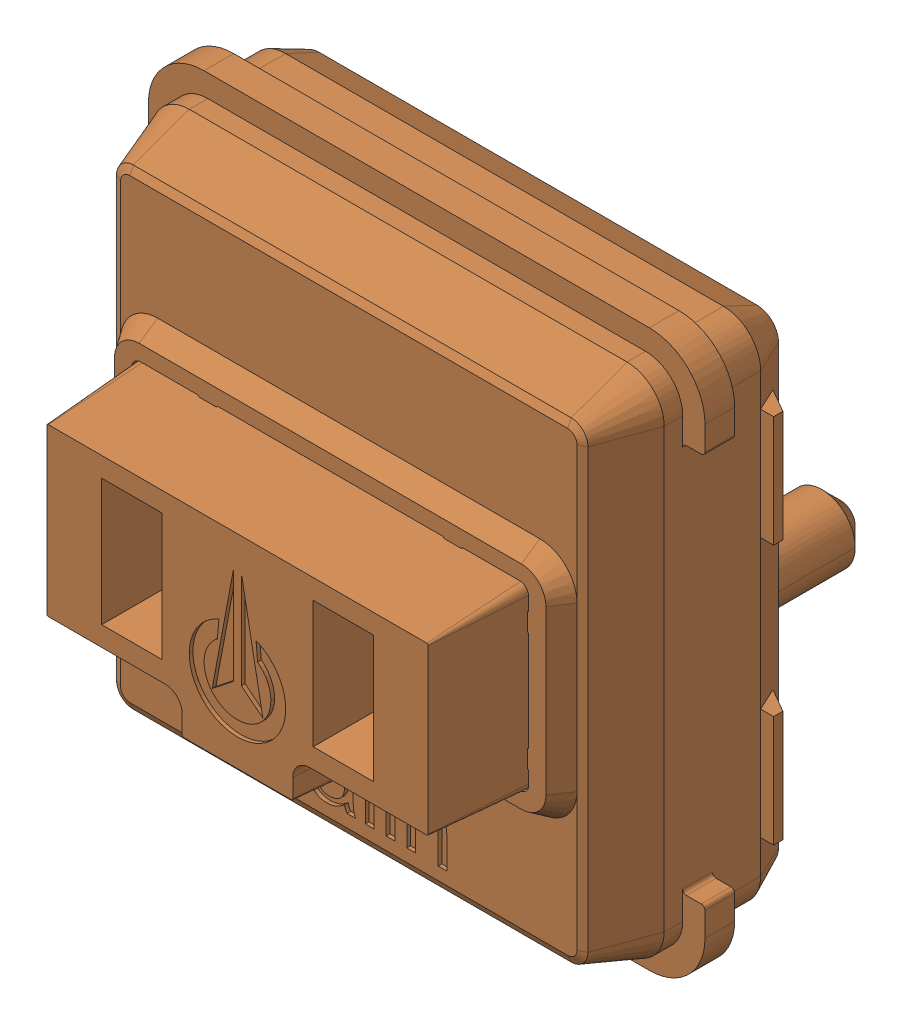
SolidWorks assembly SW1_1.step, configuration Default. Lengths in mm.
Overall size (15 15 11.1).
2 component instances, 2 part files, 0 mates.
Components (placement in the parent):
- WS2812-2020_1.step-11: WS2812-2020_1.step [Default] at (496.489 231.0345 0.3) x (1 0 0) z (0 -1 0) size (2.2 0.86 2)
- Kailh LP Choc Burnt Orange_1.step-11: Kailh LP Choc Burnt Orange_1.step [Default] at (496.3824 226.3933 2.7) x (0 -1 0) z (-1 0 0) size (15 11.1 15)
